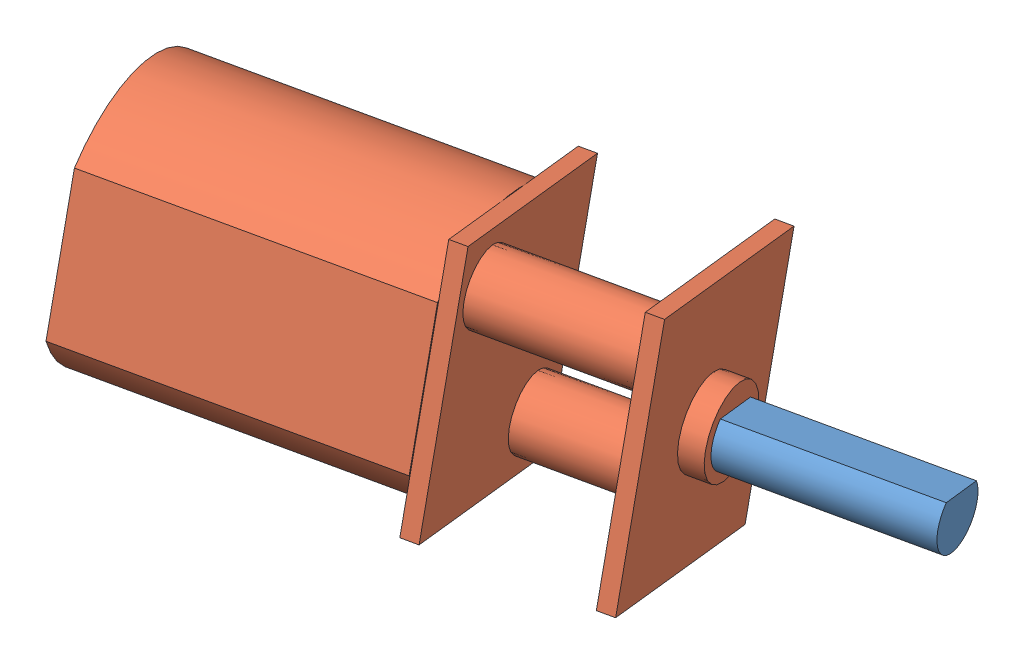
SolidWorks assembly pololu, configuration Défaut. Lengths in mm.
Overall size (34.13 15.14 18.69).
2 component instances, 2 part files, 2 mates.
Components (placement in the parent):
- nez-1: nez [Défaut] at (-0.3106 -0.8017 10.2819) x (-0.282551 -0.197171 -0.93877) z (-0.959249 0.055741 0.277008) size (2.99 2.45 9.14)
- corps-2: corps [Défaut] at (-31.1523 -1.3022 25.0217) x (-0.282539 -0.201209 -0.937916) z (0.959249 -0.055741 -0.277008) size (10.02 12.02 24.5)
Mates (geometry in assembly coordinates):
- Coïncidente1: coincident anti-aligned: plane of nez-1 through (-9.0782 -0.2922 12.8137) normal (-0.959249 0.055741 0.277008); plane of corps-2 through (-9.0782 -0.2922 12.8137) normal (0.959249 -0.055741 -0.277008)
- Coaxiale1: concentric anti-aligned: circle of nez-1; circle of corps-2
